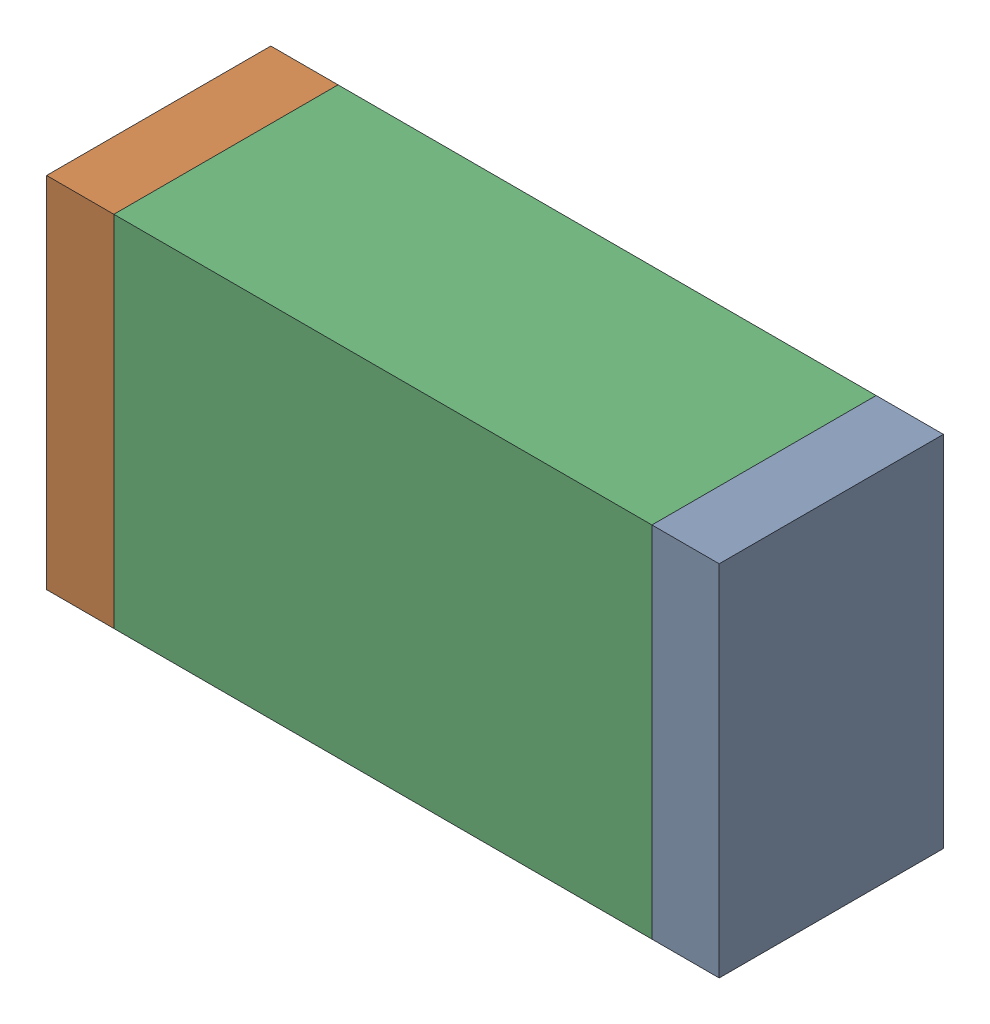
SolidWorks assembly R27, configuration Default. Lengths in mm.
Overall size (1.5 0.8 0.5).
6 component instances, 2 part files, 0 mates.
Components (placement in the parent):
- 836752496-1: 836752496 [Default] at (130.575 46 0) size (0.15 0.8 0.5)
  - Extruded_2-1: Extruded_2 [Default] at origin size (0.15 0.8 0.5)
- 836752496-2: 836752496 [Default] at (129.225 46 0) size (0.15 0.8 0.5)
  - Extruded_2-1: Extruded_2 [Default] at origin size (0.15 0.8 0.5)
- 836752368-1: 836752368 [Default] at (129.9 46 0) size (1.2 0.8 0.5)
  - Extruded-1: Extruded [Default] at origin size (1.2 0.8 0.5)
